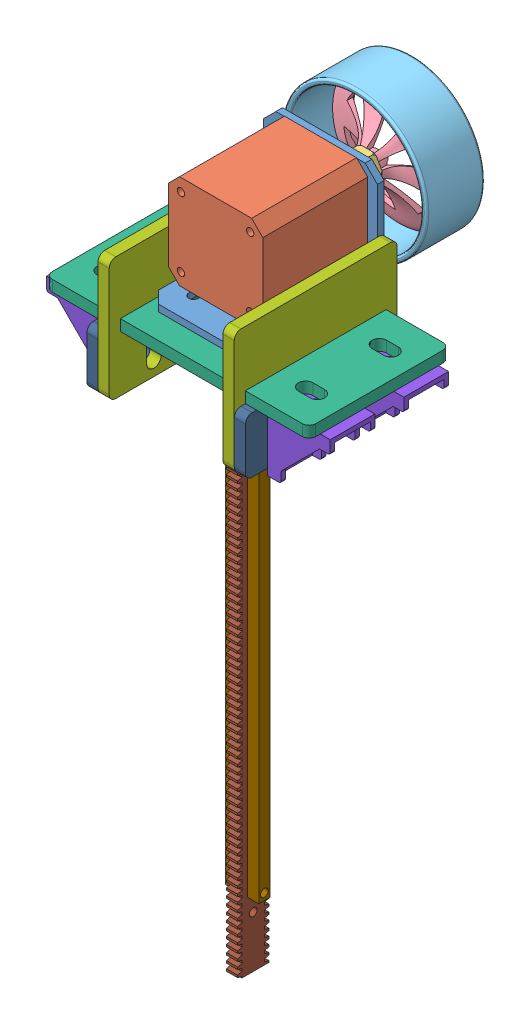
SolidWorks assembly 装配体1, configuration 默认. Lengths in mm.
Overall size (127 334.01 110.15).
18 component instances, 11 part files, 28 mates.
Components (placement in the parent):
- 电机支架-1: 电机支架 [默认] at (0.5477 -19.153 31) size (51 51 56)
- 电机驱动器-1: 电机驱动器 [默认] at (0.5477 7.847 31) size (42.3 42.3 61)
- 六角联轴器-1: 六角联轴器 [默认] at (0.5477 7.847 16) x (1 0 0) z (0 1 0) size (14 18 12.12)
- 整个车轮-1: 整个车轮 [默认] at (-1.2111 6.0898 64.1725) x (-0.823184 -0.567775 0) z (0 0 -1) size (84.94 84.94 26)
  - 轮胎-1: 轮胎 [默认] at (-2.4455 0.4479 54.1725) size (63.39 63.18 21.57)
  - 轮胎外-1: 轮胎外 [默认] at (-2.4455 0.4479 48.1725) x (0.923728 0.383049 0) z (0.383049 -0.923728 0) size (65 26 65)
- 1-1: 1 [默认] at (0.5477 -27.153 60.15) x (1 0 0) z (0 1 0) size (118 63 5)
- 2-1: 2 [默认] at (31.0477 -24.653 63.65) x (0 0 -1) z (-1 0 0) size (73 55 5)
- 2-2: 2 [默认] at (-24.9523 -24.653 63.65) x (0 0 -1) z (-1 0 0) size (73 55 5)
- 2020角件-1: 2020角件 [Default] at (36.0477 -27.153 37.15) x (0 -1 0) z (0 0 1) size (28 28 20)
- 2020角件-2: 2020角件 [Default] at (-34.9523 -27.153 90.15) x (0 -1 0) z (0 0 -1) size (28 28 20)
- 3-1: 3 [默认] at (-1.9523 -27.153 66.15) x (1 0 0) z (0 0 -1) size (38 220 5)
- 3-2: 3 [默认] at (3.0477 -27.153 61.15) x (-1 0 0) z (0 0 1) size (38 220 5)
- 4-1: 4 [默认] at (-29.9523 -39.653 63.65) x (0 0 -1) z (-1 0 0) size (73 25 5)
- 2020角件-3: 2020角件 [Default] at (-34.9523 -27.153 57.15) x (0 -1 0) z (0 0 -1) size (28 28 20)
- 4-2: 4 [默认] at (36.0477 -39.653 63.65) x (0 0 -1) z (-1 0 0) size (73 25 5)
- 2020角件-4: 2020角件 [Default] at (36.0477 -27.153 70.15) x (0 -1 0) z (0 0 1) size (28 28 20)
- 5-1: 5 [默认] at (-1.9523 -260.723 -17.3052) x (0 0 -1) z (1 0 0) size (15.81 251 15.81)
Mates (geometry in assembly coordinates):
- 同心1: concentric aligned: cylinder of 电机支架-1 through (0.5477 7.847 28) axis (0 0 1) radius 11; cylinder of 电机驱动器-1 through (0.5477 7.847 29) axis (0 0 1) radius 11
- 重合1: coincident anti-aligned: plane of 电机支架-1 through (0.5477 -19.153 31) normal (0 0 1); plane of 电机驱动器-1 through (0.5477 7.847 31) normal (0 0 -1)
- 同心2: concentric anti-aligned: cylinder of 电机支架-1 through (-14.9523 23.347 28) axis (0 0 1) radius 1.65; cylinder of 电机驱动器-1 through (-14.9523 23.347 78) axis (0 0 -1) radius 1.65
- 同心3: concentric anti-aligned: cylinder of 电机支架-1 through (16.0477 -7.653 28) axis (0 0 1) radius 1.65; cylinder of 电机驱动器-1 through (16.0477 -7.653 78) axis (0 0 -1) radius 1.65
- 同心4: concentric anti-aligned: cylinder of 电机驱动器-1 through (0.5477 7.847 7) axis (0 0 1) radius 2.5; cylinder of 六角联轴器-1 through (0.5477 7.847 39) axis (0 0 -1) radius 2.5
- 重合2: coincident anti-aligned: plane of 电机支架-1 through (0.5477 -19.153 28) normal (0 0 -1); plane of 六角联轴器-1 through (0.5477 7.847 28) normal (0 0 1)
- 同心5: concentric anti-aligned: cylinder of 六角联轴器-1 through (0.5477 7.847 28) axis (0 0 -1) radius 5.75; cylinder of 整个车轮-1/轮胎外-1 through (0.5477 7.847 -10) axis (0 0 1) radius 32.5
- 重合4: coincident anti-aligned: plane of 六角联轴器-1 through (0.5477 7.847 10) normal (0 0 -1); plane of 整个车轮-1/轮胎-1 through (5.4868 11.2537 10) normal (0 0 1)
- 重合5: coincident anti-aligned: plane of 电机支架-1 through (0.5477 -22.153 31) normal (0 -1 0); plane of 1-1 through (56.5477 -22.153 35.15) normal (0 1 0)
- 重合6: coincident aligned: plane of 电机支架-1 through (13.3977 -22.153 43.15) normal (1 0 0); plane of 1-1 through (13.3977 -22.153 77.15) normal (1 0 0)
- 同心6: concentric anti-aligned: cylinder of 电机支架-1 through (15.5477 -22.153 43.15) axis (0 1 0) radius 2.15; cylinder of 1-1 through (15.5477 -22.153 43.15) axis (0 -1 0) radius 2.15
- 重合8: coincident anti-aligned: plane of 1-1 through (56.5477 -22.153 35.15) normal (0 1 0); plane of 2-1 through (26.0477 -22.153 95.15) normal (0 -1 0)
- 重合9: coincident anti-aligned: plane of 1-1 through (-55.4523 -22.153 95.15) normal (0 0 1); plane of 2-1 through (26.0477 -27.153 95.15) normal (0 0 -1)
- 重合10: coincident anti-aligned: plane of 电机支架-1 through (26.0477 -22.153 28) normal (1 0 0); plane of 2-1 through (26.0477 -49.153 30.15) normal (-1 0 0)
- 重合12: coincident anti-aligned: plane of 1-1 through (56.5477 -27.153 35.15) normal (0 -1 0); plane of 2020角件-1 through (36.0477 -27.153 57.15) normal (0 1 0)
- 重合13: coincident aligned: plane of 1-1 through (48.2977 -32.153 50.4) normal (0 0 -1); plane of 2020角件-1 through (47.0477 -27.152 50.4) normal (0 0 -1)
- 重合14: coincident anti-aligned: plane of 1-1 through (56.5477 -27.153 35.15) normal (0 -1 0); plane of 2020角件-2 through (-34.9523 -27.153 70.15) normal (0 1 0)
- 重合16: coincident aligned: plane of 2-2 through (-29.9523 -45.653 76.9) normal (0 0 1); plane of 2020角件-2 through (-34.9513 -37.153 76.9) normal (0 0 1)
- 重合17: coincident anti-aligned: plane of 1-1 through (56.5477 -27.153 35.15) normal (0 -1 0); plane of 3-1 through (-1.9523 -27.153 61.15) normal (0 1 0)
- 重合18: coincident anti-aligned: plane of 2-2 through (-29.9523 -42.153 66.15) normal (0 0 -1); plane of 3-1 through (-1.9523 -27.153 66.15) normal (0 0 1)
- 距离1: distance = 10 mm aligned: plane of 3-1 through (-39.9523 -27.153 61.15) normal (-1 0 0); plane of 2-2 through (-29.9523 -49.153 30.15) normal (-1 0 0)
- 重合20: coincident anti-aligned: plane of 3-1 through (-39.9523 -42.153 61.15) normal (0 -1 0); plane of 4-1 through (-34.9523 -42.153 61.15) normal (0 1 0)
- 重合21: coincident anti-aligned: plane of 2-2 through (-29.9523 -49.153 30.15) normal (-1 0 0); plane of 4-1 through (-29.9523 -30.153 30.15) normal (1 0 0)
- 重合22: coincident aligned: plane of 2-2 through (-29.9523 -37.153 43.9) normal (0 0 1); plane of 4-1 through (-34.9523 -37.153 43.9) normal (0 0 1)
- 重合23: coincident anti-aligned: plane of 2020角件-2 through (-34.9523 -55.153 70.15) normal (1 0 0); plane of 4-1 through (-34.9523 -30.153 30.15) normal (-1 0 0)
- 重合24: coincident anti-aligned: plane of 2020角件-1 through (36.0477 -55.153 57.15) normal (-1 0 0); plane of 4-2 through (36.0477 -30.153 30.15) normal (1 0 0)
- 重合25: coincident anti-aligned: plane of 3-1 through (-1.9523 -247.153 61.15) normal (1 0 0); plane of 5-1 through (-1.9523 -260.723 -17.3052) normal (-1 0 0)
- 重合26: coincident anti-aligned: plane of 1-1 through (56.5477 -27.153 35.15) normal (0 -1 0); plane of 5-1 through (3.0477 -27.153 68.65) normal (0 1 0)
